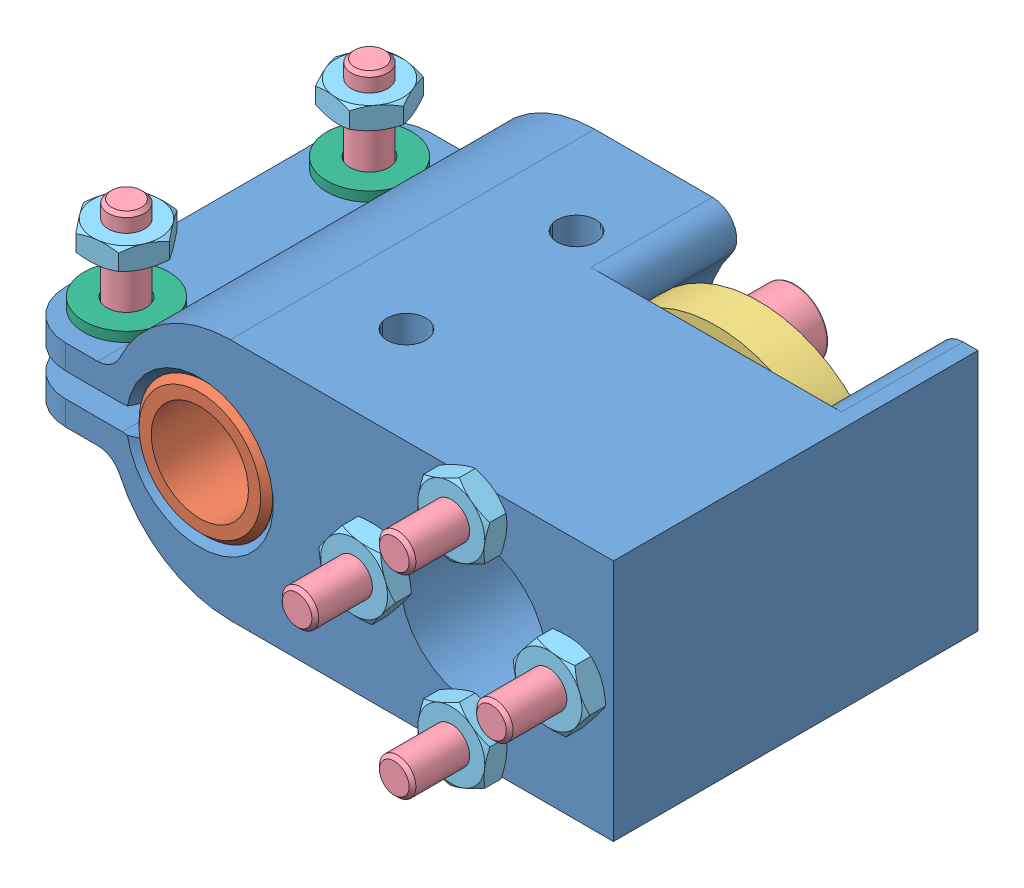
SolidWorks assembly X CHARIOT ASSY, configuration Default. Lengths in mm.
Overall size (49.4 23.51 36.69).
17 component instances, 6 part files, 17 mates.
Components (placement in the parent):
- lead x chariot-1: lead x chariot [Default] at (13.8207 -0.0483 62.5173) size (49.08 20 30.38)
- brass sleeve 30mm-2: brass sleeve 30mm [Default] at (-8.6793 -0.0483 62.5173) x (0.987351 0.158553 0) z (0 0 1) size (11 11 30)
- LeadScrew Nut 8mm x 2mmPitch (1)-1: LeadScrew Nut 8mm x 2mmPitch (1) [Default] at (13.8207 -0.0483 69.0173) x (-1 0 0) z (0 0 -1) size (22 22 16.05)
- socket head cap screw_iso-2: socket head cap screw_iso [ISO 4762 M3 x 30 - 18N] at (5.8207 -0.0483 66.0173) x (0 0 1) z (0.923728 0.383049 0) size (33 5.5 5.5)
- socket head cap screw_iso-3: socket head cap screw_iso [ISO 4762 M3 x 30 - 18N] at (13.8207 7.9517 66.0173) x (0 0 1) z (0.383049 -0.923728 0) size (33 5.5 5.5)
- socket head cap screw_iso-4: socket head cap screw_iso [ISO 4762 M3 x 30 - 18N] at (21.8207 -0.0483 66.0173) x (0 0 1) z (-0.923728 -0.383049 0) size (33 5.5 5.5)
- socket head cap screw_iso-5: socket head cap screw_iso [ISO 4762 M3 x 30 - 18N] at (13.8207 -8.0483 66.0173) x (0 0 1) z (-0.383049 0.923728 0) size (33 5.5 5.5)
- hex thin nut chamfered gradeab_iso-1: hex thin nut chamfered gradeab_iso [ISO - 4035 - M3 - N] at (21.8207 -0.0483 92.5173) x (-0.923728 -0.383049 0) z (0 0 -1) size (5.5 6.35 1.8)
- hex thin nut chamfered gradeab_iso-2: hex thin nut chamfered gradeab_iso [ISO - 4035 - M3 - N] at (13.8207 -8.0483 92.5173) x (-0.383049 0.923728 0) z (0 0 -1) size (5.5 6.35 1.8)
- hex thin nut chamfered gradeab_iso-3: hex thin nut chamfered gradeab_iso [ISO - 4035 - M3 - N] at (5.8207 -0.0483 92.5173) x (0.923728 0.383049 0) z (0 0 -1) size (5.5 6.35 1.8)
- hex thin nut chamfered gradeab_iso-4: hex thin nut chamfered gradeab_iso [ISO - 4035 - M3 - N] at (13.8207 7.9517 92.5173) x (0.383049 -0.923728 0) z (0 0 -1) size (5.5 6.35 1.8)
- socket head cap screw_iso-8: socket head cap screw_iso [ISO 4762 M3 x 10 - 10N] at (-19.7187 -2.2811 67.5173) x (0 1 0) z (0.395734 0 0.918365) size (13 5.5 5.5)
- socket head cap screw_iso-9: socket head cap screw_iso [ISO 4762 M3 x 10 - 10N] at (-19.7187 -2.2811 87.5173) x (0 1 0) z (0.6 0 0.8) size (13 5.5 5.5)
- plain washer 10673 type snl_iso-3: plain washer 10673 type snl_iso [ISO 10673-3.2-S] at (-19.7187 2.9517 67.5173) x (0 1 0) z (0 0 1) size (0.8 7 7)
- plain washer 10673 type snl_iso-4: plain washer 10673 type snl_iso [ISO 10673-3.2-S] at (-19.7187 2.9517 87.5173) x (0 1 0) z (0 0 1) size (0.8 7 7)
- hex thin nut chamfered gradeab_iso-8: hex thin nut chamfered gradeab_iso [ISO - 4035 - M3 - N] at (-19.7187 7.5189 67.5173) x (0.918365 0 -0.395734) z (0 -1 0) size (5.5 6.35 1.8)
- hex thin nut chamfered gradeab_iso-9: hex thin nut chamfered gradeab_iso [ISO - 4035 - M3 - N] at (-19.7187 7.5189 87.5173) x (0.8 0 -0.6) z (0 -1 0) size (5.5 6.35 1.8)
Mates (geometry in assembly coordinates):
- Coincidente2: coincident aligned: plane of lead x chariot-1 through (13.8207 -0.0483 62.5173) normal (0 0 -1); plane of brass sleeve 30mm-2 through (-8.6793 -0.0483 62.5173) normal (0 0 -1)
- Concentrico2: concentric anti-aligned: cylinder of lead x chariot-1 through (-8.6793 -0.0483 62.5163) axis (0 0 1) radius 5.05; cylinder of brass sleeve 30mm-2 through (-8.6793 -0.0483 92.5173) axis (0 0 -1) radius 5.5
- Coincidente5: coincident anti-aligned: plane of lead x chariot-1 through (13.8207 -0.0483 72.5173) normal (0 0 -1); plane of LeadScrew Nut 8mm x 2mmPitch (1)-1 through (13.8207 -0.0483 72.5173) normal (0 0 1)
- Concentrico3: concentric anti-aligned: cylinder of lead x chariot-1 through (13.8207 -0.0483 62.5163) axis (0 0 1) radius 5.05; cylinder of LeadScrew Nut 8mm x 2mmPitch (1)-1 through (13.8207 -0.0483 82.5173) axis (0 0 -1) radius 5.1
- Concentrico4: concentric anti-aligned: cylinder of lead x chariot-1 through (21.8207 -0.0483 62.5163) axis (0 0 1) radius 1.6; cylinder of LeadScrew Nut 8mm x 2mmPitch (1)-1 through (21.8207 -0.0483 72.5173) axis (0 0 -1) radius 1.75
- Concentrico5: concentric anti-aligned: cylinder of lead x chariot-1 through (5.8207 -0.0483 62.5163) axis (0 0 1) radius 1.6; cylinder of socket head cap screw_iso-2 through (5.8207 -0.0483 34.2673) axis (0 0 -1) radius 2.75
- Coincidente7: coincident anti-aligned: plane of LeadScrew Nut 8mm x 2mmPitch (1)-1 through (13.8207 -0.0483 69.0173) normal (0 0 -1); plane of socket head cap screw_iso-2 through (6.8741 -2.5886 69.0173) normal (0 0 1)
- Concentrico8: concentric aligned: cylinder of socket head cap screw_iso-4 through (21.8207 -0.0483 34.2673) axis (0 0 -1) radius 1.5; cylinder of hex thin nut chamfered gradeab_iso-1 through (21.8207 -0.0483 117.5548) axis (0 0 -1) radius 1.5
- Coincidente9: coincident anti-aligned: plane of lead x chariot-1 through (13.8207 -0.0483 92.5173) normal (0 0 1); plane of hex thin nut chamfered gradeab_iso-1 through (20.6043 2.8849 92.5173) normal (0 0 -1)
- Concentrico11: concentric aligned: cylinder of lead x chariot-1 through (-19.7187 9.9527 67.5173) axis (0 -1 0) radius 1.6; cylinder of socket head cap screw_iso-8 through (-19.7187 -34.0311 67.5173) axis (0 -1 0) radius 2.75
- Concentrico12: concentric aligned: cylinder of lead x chariot-1 through (-19.7187 9.9527 87.5173) axis (0 -1 0) radius 1.6; cylinder of socket head cap screw_iso-9 through (-19.7187 -34.0311 87.5173) axis (0 -1 0) radius 2.75
- Concentrico15: concentric aligned: cylinder of lead x chariot-1 through (-19.7187 9.9527 67.5173) axis (0 -1 0) radius 1.6; cylinder of plain washer 10673 type snl_iso-3 through (-19.7187 3.7517 67.5173) axis (0 -1 0) radius 1.6
- Coincidente19: coincident anti-aligned: plane of lead x chariot-1 through (-15.7187 2.9517 52.5173) normal (0 1 0); plane of plain washer 10673 type snl_iso-3 through (-19.7187 2.9517 67.5173) normal (0 -1 0)
- Concentrico16: concentric aligned: cylinder of lead x chariot-1 through (-19.7187 9.9527 87.5173) axis (0 -1 0) radius 1.6; cylinder of plain washer 10673 type snl_iso-4 through (-19.7187 3.7517 87.5173) axis (0 -1 0) radius 1.6
- Coincidente20: coincident anti-aligned: plane of lead x chariot-1 through (-15.7187 2.9517 52.5173) normal (0 1 0); plane of plain washer 10673 type snl_iso-4 through (-19.7187 2.9517 87.5173) normal (0 -1 0)
- Concentrico19: concentric aligned: cylinder of socket head cap screw_iso-8 through (-19.7187 -34.0311 67.5173) axis (0 -1 0) radius 1.5; cylinder of hex thin nut chamfered gradeab_iso-8 through (-19.7187 9.3189 67.5173) axis (0 -1 0) radius 1.25
- Concentrico20: concentric aligned: cylinder of socket head cap screw_iso-9 through (-19.7187 -34.0311 87.5173) axis (0 -1 0) radius 1.5; cylinder of hex thin nut chamfered gradeab_iso-9 through (-19.7187 9.3189 87.5173) axis (0 -1 0) radius 1.25
